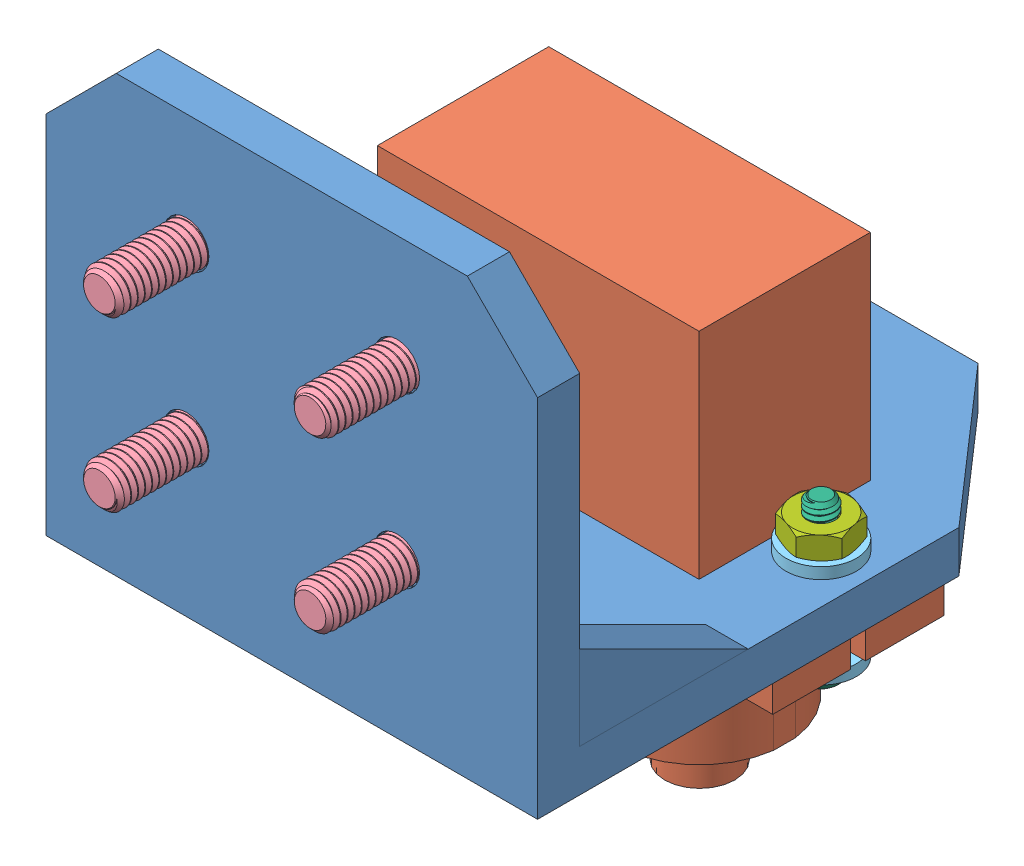
SolidWorks assembly 9g_180_servo_motor_assembly, configuration Default. Lengths in mm.
Overall size (35 45.2 47.2).
18 component instances, 7 part files, 36 mates.
Components (placement in the parent):
- 9g_180_servo_motor_mount-1: 9g_180_servo_motor_mount [Default] at (53.1577 10.3997 -8.3092) size (35 31 40.8)
- 9g_180_servo_motor-1: 9g_180_servo_motor [Default] at (31.8266 28.6997 40.6214) x (-1 0 0) z (0 0 1) size (33.4 32.5 12.2)
- M3_95610A330_Nylon Plastic Washer-1: M3_95610A330_Nylon Plastic Washer [95610A330] at (27.8766 21.3997 66.9654) x (0.999918 -0.012842 0) z (0 0 1) size (8 8 0.8)
- M3_10mm_98511A731_Aluminum Socket Head Screw-1: M3_10mm_98511A731_Aluminum Socket Head Screw [98511A731] at (27.8766 21.3997 70.0654) x (0 0 -1) z (0.955731 0.294242 0) size (13.33 5.68 5.68)
- M3_10mm_98511A731_Aluminum Socket Head Screw-2: M3_10mm_98511A731_Aluminum Socket Head Screw [98511A731] at (12.8766 21.3997 70.0654) x (0 0 -1) z (0.198195 0.980163 0) size (13.33 5.68 5.68)
- M3_10mm_98511A731_Aluminum Socket Head Screw-3: M3_10mm_98511A731_Aluminum Socket Head Screw [98511A731] at (12.8766 33.3997 70.0654) x (0 0 -1) z (0.517055 0.855952 0) size (13.33 5.68 5.68)
- M3_10mm_98511A731_Aluminum Socket Head Screw-4: M3_10mm_98511A731_Aluminum Socket Head Screw [98511A731] at (27.8766 33.3997 70.0654) x (0 0 -1) z (0.086125 -0.996284 0) size (13.33 5.68 5.68)
- M3_95610A330_Nylon Plastic Washer-2: M3_95610A330_Nylon Plastic Washer [95610A330] at (12.8766 33.3997 66.9654) x (0.812897 -0.582407 0) z (0 0 1) size (8 8 0.8)
- M3_95610A330_Nylon Plastic Washer-3: M3_95610A330_Nylon Plastic Washer [95610A330] at (27.8766 33.3997 66.9654) x (0.929624 -0.368509 0) z (0 0 1) size (8 8 0.8)
- M3_95610A330_Nylon Plastic Washer-4: M3_95610A330_Nylon Plastic Washer [95610A330] at (12.8766 21.3997 66.9654) x (0.877475 -0.479623 0) z (0 0 1) size (8 8 0.8)
- M2_95610A310_Nylon Plastic Washer-1: M2_95610A310_Nylon Plastic Washer [95610A310] at (6.4266 7.2997 46.7214) x (-0.650619 0 0.759404) z (0 -1 0) size (5 5 0.8)
- M2_95610A310_Nylon Plastic Washer-2: M2_95610A310_Nylon Plastic Washer [95610A310] at (6.4266 13.7997 46.7214) x (-0.975871 0 -0.218349) z (0 -1 0) size (5 5 0.8)
- M2_10mm_98511A729_Aluminum Socket Head Screw-1: M2_10mm_98511A729_Aluminum Socket Head Screw [91239A706] at (6.4266 11.2497 46.7214) x (-0.113555 0 -0.993532) z (0 -1 0) size (3.5 3.5 11.53)
- M2_90592A075_Steel Hex Nut-1: M2_90592A075_Steel Hex Nut [90592A075] at (6.4266 14.9997 46.7214) x (0.911647 0 0.410973) z (-0.410973 0 0.911647) size (4 1.91 4.62)
- M2_10mm_98511A729_Aluminum Socket Head Screw-2: M2_10mm_98511A729_Aluminum Socket Head Screw [91239A706] at (34.4266 11.2497 46.7214) x (-0.843079 0 0.53779) z (0 -1 0) size (3.5 3.5 11.53)
- M2_95610A310_Nylon Plastic Washer-3: M2_95610A310_Nylon Plastic Washer [95610A310] at (34.4266 13.7997 46.7214) x (-0.063368 0 0.99799) z (0 1 0) size (5 5 0.8)
- M2_95610A310_Nylon Plastic Washer-4: M2_95610A310_Nylon Plastic Washer [95610A310] at (34.4266 7.2997 46.7214) x (0.210592 0 0.977574) z (0 1 0) size (5 5 0.8)
- M2_90592A075_Steel Hex Nut-2: M2_90592A075_Steel Hex Nut [90592A075] at (34.4266 14.9997 46.7214) x (0.6677 0 0.744431) z (-0.744431 0 0.6677) size (4 1.91 4.62)
Mates (geometry in assembly coordinates):
- Coincident1: coincident anti-aligned: plane of 9g_180_servo_motor_mount-1 through (8.9266 13.3997 40.6214) normal (1 0 0); plane of servo motor-1 through (8.9266 28.6997 52.8214) normal (-1 0 0)
- Coincident2: coincident anti-aligned: plane of 9g_180_servo_motor_mount-1 through (31.8266 13.3997 52.8214) normal (0 0 -1); plane of servo motor-1 through (31.8266 28.6997 52.8214) normal (0 0 1)
- Coincident3: coincident anti-aligned: plane of 9g_180_servo_motor_mount-1 through (53.1577 10.3997 -8.3092) normal (0 -1 0); plane of servo motor-1 through (8.9266 10.3997 52.8214) normal (0 1 0)
- Concentric1: concentric aligned: cylinder of 9g_180_servo_motor_mount-1 through (27.8766 21.3997 67.3654) axis (0 0 -1) radius 1.6; cylinder of M3_95610A330_Nylon Plastic Washer-1 through (27.8766 21.3997 67.3654) axis (0 0 -1) radius 1.6
- Coincident4: coincident anti-aligned: plane of 9g_180_servo_motor_mount-1 through (2.8766 41.3997 67.3654) normal (0 0 -1); plane of M3_95610A330_Nylon Plastic Washer-1 through (27.8766 21.3997 67.3654) normal (0 0 1)
- Concentric2: concentric aligned: cylinder of 9g_180_servo_motor_mount-1 through (27.8766 21.3997 67.3654) axis (0 0 -1) radius 1.6; cylinder of M3_10mm_98511A731_Aluminum Socket Head Screw-1 through (27.8766 21.3997 63.5654) axis (0 0 -1) radius 1.5
- Coincident5: coincident anti-aligned: plane of M3_95610A330_Nylon Plastic Washer-1 through (27.8766 21.3997 66.5654) normal (0 0 -1); plane of M3_10mm_98511A731_Aluminum Socket Head Screw-1 through (27.041 24.114 66.5654) normal (0 0 1)
- Concentric3: concentric aligned: cylinder of 9g_180_servo_motor_mount-1 through (12.8766 21.3997 67.3654) axis (0 0 -1) radius 1.6; cylinder of M3_95610A330_Nylon Plastic Washer-4 through (12.8766 21.3997 67.3654) axis (0 0 -1) radius 1.6
- Coincident6: coincident anti-aligned: plane of 9g_180_servo_motor_mount-1 through (2.8766 41.3997 67.3654) normal (0 0 -1); plane of M3_95610A330_Nylon Plastic Washer-4 through (12.8766 21.3997 67.3654) normal (0 0 1)
- Concentric4: concentric aligned: cylinder of 9g_180_servo_motor_mount-1 through (12.8766 33.3997 67.3654) axis (0 0 -1) radius 1.6; cylinder of M3_95610A330_Nylon Plastic Washer-2 through (12.8766 33.3997 67.3654) axis (0 0 -1) radius 1.6
- Concentric5: concentric aligned: cylinder of 9g_180_servo_motor_mount-1 through (27.8766 33.3997 67.3654) axis (0 0 -1) radius 1.6; cylinder of M3_95610A330_Nylon Plastic Washer-3 through (27.8766 33.3997 67.3654) axis (0 0 -1) radius 1.6
- Coincident7: coincident anti-aligned: plane of 9g_180_servo_motor_mount-1 through (2.8766 41.3997 67.3654) normal (0 0 -1); plane of M3_95610A330_Nylon Plastic Washer-3 through (27.8766 33.3997 67.3654) normal (0 0 1)
- Coincident8: coincident anti-aligned: plane of 9g_180_servo_motor_mount-1 through (2.8766 41.3997 67.3654) normal (0 0 -1); plane of M3_95610A330_Nylon Plastic Washer-2 through (12.8766 33.3997 67.3654) normal (0 0 1)
- Concentric6: concentric aligned: cylinder of 9g_180_servo_motor_mount-1 through (12.8766 21.3997 67.3654) axis (0 0 -1) radius 1.6; cylinder of M3_10mm_98511A731_Aluminum Socket Head Screw-2 through (12.8766 21.3997 63.5654) axis (0 0 -1) radius 1.5
- Concentric7: concentric aligned: cylinder of 9g_180_servo_motor_mount-1 through (12.8766 33.3997 67.3654) axis (0 0 -1) radius 1.6; cylinder of M3_10mm_98511A731_Aluminum Socket Head Screw-3 through (12.8766 33.3997 63.5654) axis (0 0 -1) radius 1.5
- Concentric8: concentric aligned: cylinder of 9g_180_servo_motor_mount-1 through (27.8766 33.3997 67.3654) axis (0 0 -1) radius 1.6; cylinder of M3_10mm_98511A731_Aluminum Socket Head Screw-4 through (27.8766 33.3997 63.5654) axis (0 0 -1) radius 1.5
- Coincident9: coincident anti-aligned: plane of M3_10mm_98511A731_Aluminum Socket Head Screw-4 through (30.7061 33.6443 66.5654) normal (0 0 1); plane of M3_95610A330_Nylon Plastic Washer-3 through (27.8766 33.3997 66.5654) normal (0 0 -1)
- Coincident10: coincident aligned: plane of M3_95610A330_Nylon Plastic Washer-4 through (12.8766 21.3997 66.5654) normal (0 0 -1); circle of M3_10mm_98511A731_Aluminum Socket Head Screw-2
- Coincident12: coincident anti-aligned: plane of 9g_180_servo_motor-1 through (8.9266 7.6997 52.8214) normal (0 -1 0); plane of M2_95610A310_Nylon Plastic Washer-1 through (6.4266 7.6997 46.7214) normal (0 1 0)
- Coincident14: coincident anti-aligned: plane of 9g_180_servo_motor_mount-1 through (53.1577 13.3997 -8.3092) normal (0 1 0); plane of M2_95610A310_Nylon Plastic Washer-2 through (6.4266 13.3997 46.7214) normal (0 -1 0)
- Concentric14: concentric anti-aligned: cylinder of M2_95610A310_Nylon Plastic Washer-1 through (6.4266 6.8997 46.7214) axis (0 1 0) radius 1.1; cylinder of M2_10mm_98511A729_Aluminum Socket Head Screw-1 through (6.4266 5.5997 46.7214) axis (0 -1 0) radius 1
- Coincident15: coincident anti-aligned: plane of M2_95610A310_Nylon Plastic Washer-1 through (6.4266 6.8997 46.7214) normal (0 -1 0); plane of M2_10mm_98511A729_Aluminum Socket Head Screw-1 through (4.6879 6.8997 46.9202) normal (0 1 0)
- Concentric15: concentric aligned: cylinder of 9g_180_servo_motor_mount-1 through (6.4266 13.3997 46.7214) axis (0 -1 0) radius 1.3; cylinder of M2_10mm_98511A729_Aluminum Socket Head Screw-1 through (6.4266 5.5997 46.7214) axis (0 -1 0) radius 1
- Concentric16: concentric anti-aligned: cylinder of M2_95610A310_Nylon Plastic Washer-2 through (6.4266 13.3997 46.7214) axis (0 1 0) radius 1.1; cylinder of M2_10mm_98511A729_Aluminum Socket Head Screw-1 through (6.4266 5.5997 46.7214) axis (0 -1 0) radius 1
- Coincident16: coincident aligned: line of M2_10mm_98511A729_Aluminum Socket Head Screw-1 through (6.4266 16.5797 46.7214) axis (0 -1 0); line of M2_90592A075_Steel Hex Nut-1 through (6.4266 14.8008 46.7214) axis (0 -1 0)
- Screw1: screw = 0.4 aligned: cylinder of M2_10mm_98511A729_Aluminum Socket Head Screw-1 through (6.4266 5.5997 46.7214) axis (0 -1 0) radius 1; cylinder of M2_90592A075_Steel Hex Nut-1 through (6.4266 15.7997 46.7214) axis (0 -1 0) radius 1
- LimitDistance1: limit distance = 0 mm anti-aligned: plane of M2_95610A310_Nylon Plastic Washer-2 through (6.4266 14.1997 46.7214) normal (0 1 0); plane of M2_90592A075_Steel Hex Nut-1 through (5.0779 14.1997 44.8468) normal (0 -1 0)
- Concentric17: concentric aligned: cylinder of M2_10mm_98511A729_Aluminum Socket Head Screw-2 through (34.4266 5.5997 46.7214) axis (0 -1 0) radius 1; cylinder of M2_95610A310_Nylon Plastic Washer-4 through (34.4266 7.6997 46.7214) axis (0 -1 0) radius 1.1
- Coincident17: coincident anti-aligned: plane of M2_10mm_98511A729_Aluminum Socket Head Screw-2 through (35.3678 6.8997 48.1968) normal (0 1 0); plane of M2_95610A310_Nylon Plastic Washer-4 through (34.4266 6.8997 46.7214) normal (0 -1 0)
- Concentric18: concentric aligned: cylinder of 9g_180_servo_motor_mount-1 through (34.4266 13.3997 46.7214) axis (0 -1 0) radius 1.3; cylinder of M2_10mm_98511A729_Aluminum Socket Head Screw-2 through (34.4266 5.5997 46.7214) axis (0 -1 0) radius 1
- Coincident18: coincident anti-aligned: plane of 9g_180_servo_motor-1 through (37.0766 7.6997 52.8214) normal (0 -1 0); plane of M2_95610A310_Nylon Plastic Washer-4 through (34.4266 7.6997 46.7214) normal (0 1 0)
- Concentric19: concentric aligned: cylinder of M2_10mm_98511A729_Aluminum Socket Head Screw-2 through (34.4266 5.5997 46.7214) axis (0 -1 0) radius 1; cylinder of M2_95610A310_Nylon Plastic Washer-3 through (34.4266 14.1997 46.7214) axis (0 -1 0) radius 1.1
- Coincident19: coincident anti-aligned: plane of 9g_180_servo_motor_mount-1 through (53.1577 13.3997 -8.3092) normal (0 1 0); plane of M2_95610A310_Nylon Plastic Washer-3 through (34.4266 13.3997 46.7214) normal (0 -1 0)
- Coincident20: coincident aligned: line of M2_10mm_98511A729_Aluminum Socket Head Screw-2 through (34.4266 16.5797 46.7214) axis (0 -1 0); line of M2_90592A075_Steel Hex Nut-2 through (34.4266 14.8008 46.7214) axis (0 -1 0)
- Screw2: screw = 0.4 aligned: cylinder of M2_10mm_98511A729_Aluminum Socket Head Screw-2 through (34.4266 5.5997 46.7214) axis (0 -1 0) radius 1; cylinder of M2_90592A075_Steel Hex Nut-2 through (34.4266 15.7997 46.7214) axis (0 -1 0) radius 1
- LimitDistance2: limit distance = 0 mm anti-aligned: plane of M2_90592A075_Steel Hex Nut-2 through (33.9508 14.1997 44.4616) normal (0 -1 0); plane of M2_95610A310_Nylon Plastic Washer-3 through (34.4266 14.1997 46.7214) normal (0 1 0)
